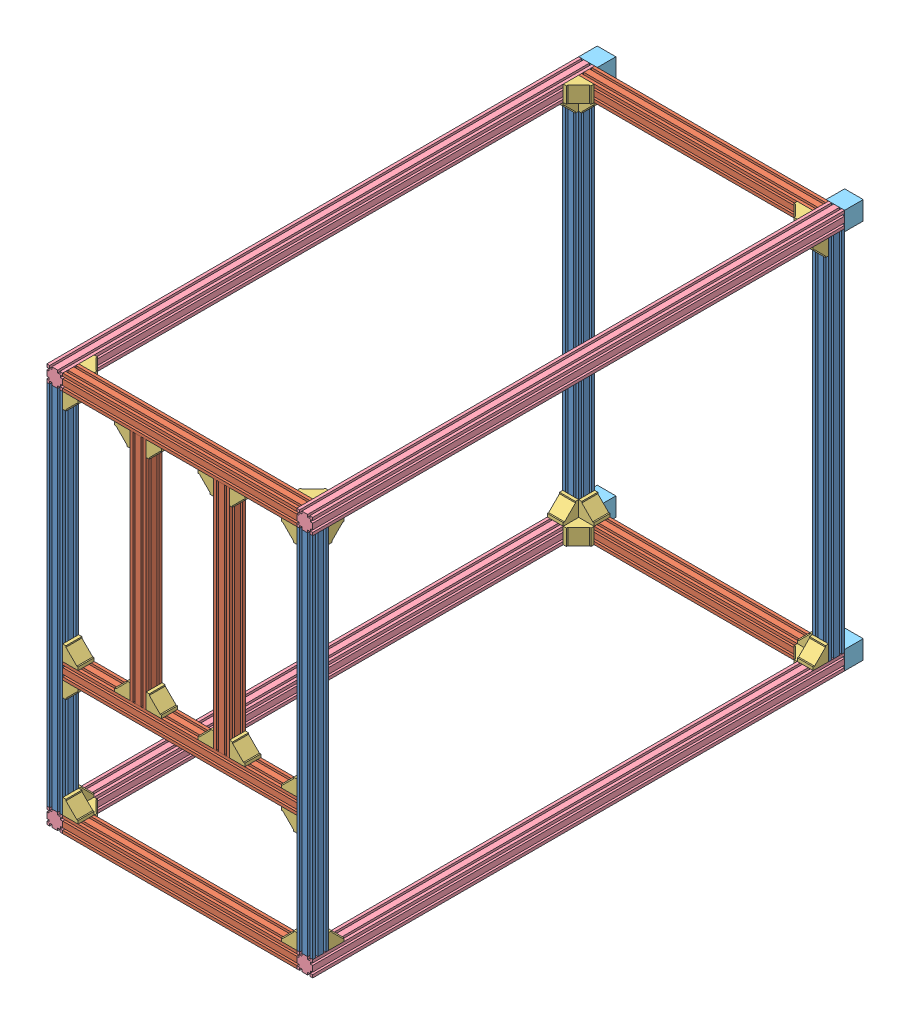
SolidWorks assembly 框架, configuration 默认. Lengths in mm.
Overall size (1000 1500 2070).
55 component instances, 5 part files, 161 mates.
Components (placement in the parent):
- 框架（水平 大）-1: 框架（水平 大） [默认] at (-98.7964 -668.0959 30) size (60 1380 60)
- 框架（水平 大）-2: 框架（水平 大） [默认] at (841.2036 -668.0959 30) size (60 1380 60)
- 框架（水平 小）-1: 框架（水平 小） [默认] at (841.2036 711.9041 30) x (0 1 0) z (0 0 1) size (60 880 60)
- 框架（水平 小）-2: 框架（水平 小） [默认] at (841.2036 -228.0959 30) x (0 1 0) z (0 0 1) size (60 880 60)
- 框架（水平 小）-6: 框架（水平 小） [默认] at (841.2036 -728.0959 30) x (0 1 0) z (0 0 1) size (60 880 60)
- 外角件-1: 外角件 [默认] at (-38.7964 -668.0959 -30) size (58 58 60)
- 外角件-2: 外角件 [默认] at (841.2036 -668.0959 -30) x (0 1 0) z (0 0 1) size (58 58 60)
- 外角件-3: 外角件 [默认] at (841.2036 -228.0959 -30) x (-1 0 0) z (0 0 1) size (58 58 60)
- 外角件-4: 外角件 [默认] at (-38.7964 -228.0959 30) x (1 0 0) z (0 0 -1) size (58 58 60)
- 外角件-5: 外角件 [默认] at (-38.7964 -168.0959 -30) size (58 58 60)
- 外角件-6: 外角件 [默认] at (527.8703 -168.0959 -30) x (0 1 0) z (0 0 1) size (58 58 60)
- 外角件-7: 外角件 [默认] at (-38.7964 711.9041 -30) x (0 -1 0) z (0 0 1) size (58 58 60)
- 外角件-8: 外角件 [默认] at (527.8703 711.9041 30) x (0 -1 0) z (0 0 -1) size (58 58 60)
- 外角件-9: 外角件 [默认] at (587.8703 -168.0959 -30) size (58 58 60)
- 外角件-10: 外角件 [默认] at (841.2036 -168.0959 -30) x (0 1 0) z (0 0 1) size (58 58 60)
- 外角件-11: 外角件 [默认] at (587.8703 711.9041 -30) x (0 -1 0) z (0 0 1) size (58 58 60)
- 外角件-12: 外角件 [默认] at (841.2036 711.9041 -30) x (-1 0 0) z (0 0 1) size (58 58 60)
- 框架（竖直）-1: 框架（竖直） [默认] at (-38.7964 771.9041 30) x (0 -1 0) z (1 0 0) size (60 2000 60)
- 框架（竖直）-2: 框架（竖直） [默认] at (901.2036 711.9041 30) x (-1 0 0) z (0 -1 0) size (60 2000 60)
- 框架（竖直）-3: 框架（竖直） [默认] at (-98.7964 -728.0959 -1970) x (1 0 0) z (0 -1 0) size (60 2000 60)
- 框架（竖直）-4: 框架（竖直） [默认] at (841.2036 -668.0959 30) x (1 0 0) z (0 1 0) size (60 2000 60)
- 框架（水平 小）-7: 框架（水平 小） [默认] at (841.2036 711.9041 -1970) x (0 0 1) z (0 -1 0) size (60 880 60)
- 框架（水平 小）-8: 框架（水平 小） [默认] at (-38.7964 -668.0959 -1910) x (0 -1 0) z (0 0 1) size (60 880 60)
- 框架（水平 大）-3: 框架（水平 大） [默认] at (901.2036 -668.0959 -1910) x (0 0 -1) z (1 0 0) size (60 1380 60)
- 框架（水平 大）-4: 框架（水平 大） [默认] at (-98.7964 -668.0959 -1910) size (60 1380 60)
- 外角件-13: 外角件 [默认] at (-38.7964 -668.0959 -1970) size (58 58 60)
- 外角件-14: 外角件 [默认] at (841.2036 711.9041 -1970) x (-1 0 0) z (0 0 1) size (58 58 60)
- 外角件-15: 外角件 [默认] at (841.2036 -668.0959 -1970) x (0 1 0) z (0 0 1) size (58 58 60)
- 外角件-16: 外角件 [默认] at (-38.7964 711.9041 -1910) x (1 0 0) z (0 0 -1) size (58 58 60)
- 外角件-17: 外角件 [默认] at (-98.7964 711.9041 -30) x (0 -1 0) z (1 0 0) size (58 58 60)
- 外角件-18: 外角件 [默认] at (841.2036 -668.0959 -30) x (0 0 -1) z (1 0 0) size (58 58 60)
- 外角件-19: 外角件 [默认] at (-38.7964 711.9041 -1910) x (0 -1 0) z (-1 0 0) size (58 58 60)
- 外角件-20: 外角件 [默认] at (901.2036 -668.0959 -1910) x (0 0 1) z (-1 0 0) size (58 58 60)
- 外角件-21: 外角件 [默认] at (841.2036 711.9041 -30) x (0 -1 0) z (1 0 0) size (58 58 60)
- 外角件-22: 外角件 [默认] at (841.2036 771.9041 -1910) x (0 0 1) z (0 -1 0) size (58 58 60)
- 外角件-23: 外角件 [默认] at (-98.7964 -668.0959 -30) x (0 0 -1) z (1 0 0) size (58 58 60)
- 外角件-24: 外角件 [默认] at (-38.7964 -668.0959 -1910) x (0 0 1) z (-1 0 0) size (58 58 60)
- 外角件-25: 外角件 [默认] at (841.2036 -668.0959 -1910) x (0 0 1) z (0 -1 0) size (58 58 60)
- 外角件-26: 外角件 [默认] at (-38.7964 -728.0959 -30) x (1 0 0) z (0 1 0) size (58 58 60)
- 外角件-27: 外角件 [默认] at (841.2036 -728.0959 -30) x (0 0 -1) z (0 1 0) size (58 58 60)
- 外角件-28: 外角件 [默认] at (-38.7964 711.9041 -30) x (1 0 0) z (0 1 0) size (58 58 60)
- 外角件-29: 外角件 [默认] at (-38.7964 -668.0959 -1910) x (1 0 0) z (0 -1 0) size (58 58 60)
- 外角件-30: 外角件 [默认] at (841.2036 711.9041 -1910) x (0 0 1) z (1 0 0) size (58 58 60)
- 外角件-31: 外角件 [默认] at (-38.7964 711.9041 -1910) x (0 0 1) z (0 1 0) size (58 58 60)
- 外角件-32: 外角件 [默认] at (841.2036 711.9041 -30) x (0 0 -1) z (0 1 0) size (58 58 60)
- 框架（水平 小）-9: 框架（水平 小） [默认] at (527.8703 -168.0959 30) size (60 880 60)
- 框架（水平 小）-10: 框架（水平 小） [默认] at (214.537 -168.0959 30) size (60 880 60)
- 外角件-33: 外角件 [默认] at (274.537 711.9041 -30) x (0 -1 0) z (0 0 1) size (58 58 60)
- 外角件-34: 外角件 [默认] at (214.537 711.9041 -30) x (-1 0 0) z (0 0 1) size (58 58 60)
- 外角件-35: 外角件 [默认] at (274.537 -168.0959 -30) size (58 58 60)
- 外角件-36: 外角件 [默认] at (214.537 -168.0959 -30) x (0 1 0) z (0 0 1) size (58 58 60)
- 支脚-1: 支脚 [默认] at (831.2036 -728.0959 -1970) size (70 70 70)
- 支脚-2: 支脚 [默认] at (-98.7964 -728.0959 -1970) size (70 70 70)
- 支脚-3: 支脚 [默认] at (-98.7964 701.9041 -1970) size (70 70 70)
- 支脚-4: 支脚 [默认] at (831.2036 701.9041 -1970) size (70 70 70)
Mates (geometry in assembly coordinates):
- 重合21: coincident anti-aligned: plane of 框架（水平 大）-1 through (-38.7964 711.9041 30) normal (1 0 0); plane of 框架（水平 小）-2 through (-38.7964 -228.0959 30) normal (-1 0 0)
- 重合22: coincident anti-aligned: plane of 框架（水平 大）-1 through (-38.7964 711.9041 30) normal (1 0 0); plane of 框架（水平 小）-1 through (-38.7964 711.9041 30) normal (-1 0 0)
- 重合23: coincident aligned: plane of 框架（水平 大）-1 through (-98.7964 711.9041 30) normal (0 0 1); plane of 框架（水平 小）-1 through (-38.7964 711.9041 30) normal (0 0 1)
- 重合24: coincident aligned: plane of 框架（水平 大）-1 through (-98.7964 711.9041 30) normal (0 0 1); plane of 框架（水平 小）-2 through (-38.7964 -228.0959 30) normal (0 0 1)
- 重合29: coincident anti-aligned: plane of 框架（水平 大）-2 through (841.2036 -668.0959 30) normal (0 -1 0); plane of 框架（水平 小）-6 through (-38.7964 -668.0959 30) normal (0 1 0)
- 重合30: coincident aligned: plane of 框架（水平 大）-2 through (841.2036 711.9041 30) normal (0 0 1); plane of 框架（水平 小）-6 through (-38.7964 -728.0959 30) normal (0 0 1)
- 重合35: coincident anti-aligned: plane of 框架（水平 大）-2 through (841.2036 711.9041 30) normal (-1 0 0); plane of 框架（水平 小）-6 through (841.2036 -728.0959 30) normal (1 0 0)
- 重合37: coincident anti-aligned: plane of 框架（水平 大）-1 through (-98.7964 711.9041 30) normal (0 1 0); plane of 框架（水平 小）-1 through (-38.7964 711.9041 30) normal (0 -1 0)
- 重合40: coincident anti-aligned: plane of 框架（水平 大）-2 through (841.2036 711.9041 30) normal (-1 0 0); plane of 框架（水平 小）-2 through (841.2036 -228.0959 30) normal (1 0 0)
- 重合41: coincident aligned: plane of 框架（水平 大）-2 through (841.2036 711.9041 30) normal (0 0 1); plane of 框架（水平 小）-2 through (-38.7964 -228.0959 30) normal (0 0 1)
- 重合42: coincident anti-aligned: plane of 框架（水平 大）-1 through (-98.7964 -668.0959 30) normal (0 -1 0); plane of 框架（水平 小）-6 through (-38.7964 -668.0959 30) normal (0 1 0)
- 重合43: coincident anti-aligned: plane of 框架（水平 大）-1 through (-38.7964 711.9041 30) normal (1 0 0); plane of 外角件-1 through (-38.7964 -610.0959 30) normal (-1 0 0)
- 重合44: coincident anti-aligned: plane of 框架（水平 小）-6 through (-38.7964 -668.0959 30) normal (0 1 0); plane of 外角件-1 through (-38.7964 -668.0959 30) normal (0 -1 0)
- 重合45: coincident aligned: plane of 框架（水平 大）-1 through (-98.7964 711.9041 30) normal (0 0 1); plane of 外角件-1 through (-38.7964 -668.0959 30) normal (0 0 1)
- 重合46: coincident anti-aligned: plane of 框架（水平 小）-2 through (-38.7964 -228.0959 30) normal (0 -1 0); plane of 外角件-4 through (-38.7964 -228.0959 -30) normal (0 1 0)
- 重合47: coincident anti-aligned: plane of 框架（水平 大）-1 through (-38.7964 711.9041 30) normal (1 0 0); plane of 外角件-4 through (-38.7964 -286.0959 -30) normal (-1 0 0)
- 重合48: coincident aligned: plane of 框架（水平 大）-1 through (-98.7964 711.9041 30) normal (0 0 1); plane of 外角件-4 through (-38.7964 -228.0959 30) normal (0 0 1)
- 重合49: coincident anti-aligned: plane of 框架（水平 小）-2 through (-38.7964 -168.0959 30) normal (0 1 0); plane of 外角件-5 through (-38.7964 -168.0959 30) normal (0 -1 0)
- 重合50: coincident anti-aligned: plane of 框架（水平 大）-1 through (-38.7964 711.9041 30) normal (1 0 0); plane of 外角件-5 through (-38.7964 -110.0959 30) normal (-1 0 0)
- 重合51: coincident aligned: plane of 框架（水平 大）-1 through (-98.7964 711.9041 30) normal (0 0 1); plane of 外角件-5 through (-38.7964 -168.0959 30) normal (0 0 1)
- 重合52: coincident anti-aligned: plane of 框架（水平 小）-1 through (-38.7964 711.9041 30) normal (0 -1 0); plane of 外角件-7 through (19.2036 711.9041 30) normal (0 1 0)
- 重合53: coincident anti-aligned: plane of 框架（水平 大）-1 through (-38.7964 711.9041 30) normal (1 0 0); plane of 外角件-7 through (-38.7964 711.9041 30) normal (-1 0 0)
- 重合54: coincident aligned: plane of 框架（水平 大）-1 through (-98.7964 711.9041 30) normal (0 0 1); plane of 外角件-7 through (-38.7964 711.9041 30) normal (0 0 1)
- 重合55: coincident anti-aligned: plane of 框架（水平 小）-1 through (-38.7964 711.9041 30) normal (0 -1 0); plane of 外角件-8 through (469.8703 711.9041 -30) normal (0 1 0)
- 重合58: coincident anti-aligned: plane of 框架（水平 小）-2 through (-38.7964 -168.0959 30) normal (0 1 0); plane of 外角件-6 through (469.8703 -168.0959 30) normal (0 -1 0)
- 重合60: coincident aligned: plane of 框架（水平 小）-2 through (-38.7964 -228.0959 30) normal (0 0 1); plane of 外角件-6 through (527.8703 -168.0959 30) normal (0 0 1)
- 重合62: coincident anti-aligned: plane of 框架（水平 小）-2 through (-38.7964 -168.0959 30) normal (0 1 0); plane of 外角件-9 through (587.8703 -168.0959 30) normal (0 -1 0)
- 重合64: coincident anti-aligned: plane of 框架（水平 小）-2 through (-38.7964 -168.0959 30) normal (0 1 0); plane of 外角件-10 through (783.2036 -168.0959 30) normal (0 -1 0)
- 重合65: coincident anti-aligned: plane of 框架（水平 大）-2 through (841.2036 711.9041 30) normal (-1 0 0); plane of 外角件-10 through (841.2036 -168.0959 30) normal (1 0 0)
- 重合66: coincident aligned: plane of 框架（水平 小）-2 through (-38.7964 -228.0959 30) normal (0 0 1); plane of 外角件-10 through (841.2036 -168.0959 30) normal (0 0 1)
- 重合68: coincident anti-aligned: plane of 框架（水平 小）-2 through (-38.7964 -228.0959 30) normal (0 -1 0); plane of 外角件-3 through (841.2036 -228.0959 30) normal (0 1 0)
- 重合69: coincident anti-aligned: plane of 框架（水平 大）-2 through (841.2036 711.9041 30) normal (-1 0 0); plane of 外角件-3 through (841.2036 -286.0959 30) normal (1 0 0)
- 重合70: coincident aligned: plane of 框架（水平 小）-2 through (-38.7964 -228.0959 30) normal (0 0 1); plane of 外角件-3 through (841.2036 -228.0959 30) normal (0 0 1)
- 重合71: coincident anti-aligned: plane of 框架（水平 大）-2 through (841.2036 711.9041 30) normal (-1 0 0); plane of 外角件-2 through (841.2036 -668.0959 30) normal (1 0 0)
- 重合72: coincident anti-aligned: plane of 框架（水平 小）-6 through (-38.7964 -668.0959 30) normal (0 1 0); plane of 外角件-2 through (783.2036 -668.0959 30) normal (0 -1 0)
- 重合73: coincident aligned: plane of 框架（水平 大）-2 through (841.2036 711.9041 30) normal (0 0 1); plane of 外角件-2 through (841.2036 -668.0959 30) normal (0 0 1)
- 重合75: coincident anti-aligned: plane of 框架（水平 小）-1 through (-38.7964 711.9041 30) normal (0 -1 0); plane of 外角件-11 through (645.8703 711.9041 30) normal (0 1 0)
- 重合77: coincident anti-aligned: plane of 框架（水平 大）-2 through (841.2036 711.9041 30) normal (-1 0 0); plane of 外角件-12 through (841.2036 653.9041 30) normal (1 0 0)
- 重合78: coincident anti-aligned: plane of 框架（水平 小）-1 through (-38.7964 711.9041 30) normal (0 -1 0); plane of 外角件-12 through (841.2036 711.9041 30) normal (0 1 0)
- 重合79: coincident aligned: plane of 框架（水平 大）-2 through (841.2036 711.9041 30) normal (0 0 1); plane of 外角件-12 through (841.2036 711.9041 30) normal (0 0 1)
- 重合80: coincident aligned: plane of 框架（水平 大）-1 through (-98.7964 711.9041 30) normal (0 0 1); plane of 框架（竖直）-1 through (-38.7964 771.9041 30) normal (0 0 1)
- 重合81: coincident anti-aligned: plane of 框架（水平 大）-1 through (-98.7964 711.9041 30) normal (0 1 0); plane of 框架（竖直）-1 through (-38.7964 711.9041 -1970) normal (0 -1 0)
- 重合82: coincident anti-aligned: plane of 框架（水平 小）-1 through (-38.7964 711.9041 30) normal (-1 0 0); plane of 框架（竖直）-1 through (-38.7964 771.9041 -1970) normal (1 0 0)
- 重合83: coincident aligned: plane of 框架（竖直）-1 through (-38.7964 771.9041 30) normal (0 0 1); plane of 框架（竖直）-2 through (901.2036 711.9041 30) normal (0 0 1)
- 重合84: coincident anti-aligned: plane of 框架（水平 大）-2 through (841.2036 711.9041 30) normal (0 1 0); plane of 框架（竖直）-2 through (901.2036 711.9041 -1970) normal (0 -1 0)
- 重合85: coincident: line of 框架（水平 小）-1 through (841.2036 771.9041 -19.1) axis (0 0 -1); plane of 框架（竖直）-2 through (841.2036 711.9041 -1970) normal (-1 0 0)
- 重合86: coincident aligned: plane of 框架（竖直）-1 through (-38.7964 771.9041 30) normal (0 0 1); plane of 框架（竖直）-3 through (-98.7964 -728.0959 30) normal (0 0 1)
- 重合87: coincident anti-aligned: plane of 框架（水平 小）-6 through (-38.7964 -728.0959 30) normal (-1 0 0); plane of 框架（竖直）-3 through (-38.7964 -728.0959 30) normal (1 0 0)
- 重合88: coincident anti-aligned: plane of 框架（水平 大）-1 through (-98.7964 -668.0959 30) normal (0 -1 0); plane of 框架（竖直）-3 through (-98.7964 -668.0959 30) normal (0 1 0)
- 重合89: coincident aligned: plane of 框架（竖直）-3 through (-98.7964 -728.0959 30) normal (0 0 1); plane of 框架（竖直）-4 through (841.2036 -668.0959 30) normal (0 0 1)
- 重合90: coincident anti-aligned: plane of 框架（水平 大）-2 through (841.2036 -668.0959 30) normal (0 -1 0); plane of 框架（竖直）-4 through (841.2036 -668.0959 -1970) normal (0 1 0)
- 重合91: coincident anti-aligned: plane of 框架（水平 小）-6 through (841.2036 -728.0959 30) normal (1 0 0); plane of 框架（竖直）-4 through (841.2036 -668.0959 -1970) normal (-1 0 0)
- 重合92: coincident aligned: plane of 框架（竖直）-1 through (-98.7964 771.9041 -1970) normal (-1 0 0); plane of 框架（水平 大）-4 through (-98.7964 711.9041 -1910) normal (-1 0 0)
- 重合93: coincident anti-aligned: plane of 框架（竖直）-3 through (-98.7964 -668.0959 30) normal (0 1 0); plane of 框架（水平 大）-4 through (-98.7964 -668.0959 -1910) normal (0 -1 0)
- 重合94: coincident aligned: plane of 框架（竖直）-1 through (-38.7964 771.9041 -1970) normal (0 0 -1); plane of 框架（水平 大）-4 through (-98.7964 711.9041 -1970) normal (0 0 -1)
- 重合95: coincident aligned: plane of 框架（竖直）-2 through (901.2036 711.9041 -1970) normal (0 0 -1); plane of 框架（水平 小）-7 through (-38.7964 711.9041 -1970) normal (0 0 -1)
- 重合96: coincident anti-aligned: plane of 框架（竖直）-1 through (-38.7964 771.9041 -1970) normal (1 0 0); plane of 框架（水平 小）-7 through (-38.7964 711.9041 -1970) normal (-1 0 0)
- 重合97: coincident aligned: plane of 框架（竖直）-1 through (-38.7964 771.9041 -1970) normal (0 1 0); plane of 框架（水平 小）-7 through (-38.7964 771.9041 -1970) normal (0 1 0)
- 重合98: coincident aligned: plane of 框架（竖直）-4 through (841.2036 -668.0959 -1970) normal (0 0 -1); plane of 框架（水平 大）-3 through (901.2036 711.9041 -1970) normal (0 0 -1)
- 重合99: coincident anti-aligned: plane of 框架（竖直）-4 through (841.2036 -668.0959 -1970) normal (0 1 0); plane of 框架（水平 大）-3 through (901.2036 -668.0959 -1910) normal (0 -1 0)
- 重合100: coincident aligned: plane of 框架（竖直）-4 through (901.2036 -668.0959 -1970) normal (1 0 0); plane of 框架（水平 大）-3 through (901.2036 711.9041 -1910) normal (1 0 0)
- 重合101: coincident anti-aligned: plane of 框架（竖直）-3 through (-38.7964 -728.0959 30) normal (1 0 0); plane of 框架（水平 小）-8 through (-38.7964 -668.0959 -1910) normal (-1 0 0)
- 重合102: coincident aligned: plane of 框架（竖直）-3 through (-98.7964 -728.0959 30) normal (0 -1 0); plane of 框架（水平 小）-8 through (841.2036 -728.0959 -1910) normal (0 -1 0)
- 重合103: coincident aligned: plane of 框架（竖直）-3 through (-98.7964 -728.0959 -1970) normal (0 0 -1); plane of 框架（水平 小）-8 through (841.2036 -668.0959 -1970) normal (0 0 -1)
- 重合104: coincident aligned: plane of 框架（竖直）-2 through (901.2036 711.9041 -1970) normal (0 0 -1); plane of 外角件-14 through (841.2036 711.9041 -1970) normal (0 0 -1)
- 重合105: coincident anti-aligned: plane of 框架（水平 大）-3 through (841.2036 711.9041 -1910) normal (-1 0 0); plane of 外角件-14 through (841.2036 653.9041 -1910) normal (1 0 0)
- 重合107: coincident anti-aligned: plane of 框架（水平 小）-7 through (-38.7964 711.9041 -1970) normal (0 -1 0); plane of 外角件-14 through (841.2036 711.9041 -1910) normal (0 1 0)
- 重合108: coincident aligned: plane of 框架（水平 大）-4 through (-98.7964 711.9041 -1910) normal (0 0 1); plane of 外角件-13 through (-38.7964 -668.0959 -1910) normal (0 0 1)
- 重合109: coincident anti-aligned: plane of 框架（水平 小）-8 through (841.2036 -668.0959 -1910) normal (0 1 0); plane of 外角件-13 through (-38.7964 -668.0959 -1910) normal (0 -1 0)
- 重合110: coincident aligned: line of 框架（水平 大）-4 through (-38.7964 711.9041 -1910) axis (0 -1 0); line of 外角件-13 through (-38.7964 -610.0959 -1910) axis (0 -1 0)
- 重合111: coincident anti-aligned: plane of 框架（水平 大）-4 through (-38.7964 711.9041 -1910) normal (1 0 0); plane of 外角件-16 through (-38.7964 653.9041 -1970) normal (-1 0 0)
- 重合112: coincident anti-aligned: plane of 框架（水平 小）-7 through (-38.7964 711.9041 -1970) normal (0 -1 0); plane of 外角件-16 through (-38.7964 711.9041 -1970) normal (0 1 0)
- 重合113: coincident aligned: plane of 框架（水平 大）-4 through (-98.7964 711.9041 -1910) normal (0 0 1); plane of 外角件-16 through (-38.7964 711.9041 -1910) normal (0 0 1)
- 重合114: coincident anti-aligned: plane of 框架（水平 小）-8 through (841.2036 -668.0959 -1910) normal (0 1 0); plane of 外角件-15 through (783.2036 -668.0959 -1910) normal (0 -1 0)
- 重合115: coincident anti-aligned: plane of 框架（水平 大）-3 through (841.2036 711.9041 -1910) normal (-1 0 0); plane of 外角件-15 through (841.2036 -668.0959 -1910) normal (1 0 0)
- 重合116: coincident aligned: plane of 框架（水平 小）-8 through (841.2036 -668.0959 -1910) normal (0 0 1); plane of 外角件-15 through (841.2036 -668.0959 -1910) normal (0 0 1)
- 重合117: coincident anti-aligned: plane of 框架（竖直）-1 through (-38.7964 711.9041 -1970) normal (0 -1 0); plane of 外角件-17 through (-38.7964 711.9041 -88) normal (0 1 0)
- 重合118: coincident anti-aligned: plane of 框架（水平 大）-1 through (-98.7964 711.9041 -30) normal (0 0 -1); plane of 外角件-17 through (-38.7964 711.9041 -30) normal (0 0 1)
- 重合119: coincident aligned: plane of 框架（竖直）-1 through (-98.7964 771.9041 -1970) normal (-1 0 0); plane of 外角件-17 through (-98.7964 711.9041 -30) normal (-1 0 0)
- 重合120: coincident anti-aligned: plane of 框架（水平 大）-2 through (841.2036 711.9041 -30) normal (0 0 -1); plane of 外角件-21 through (901.2036 711.9041 -30) normal (0 0 1)
- 重合121: coincident anti-aligned: plane of 框架（竖直）-2 through (901.2036 711.9041 -1970) normal (0 -1 0); plane of 外角件-21 through (901.2036 711.9041 -88) normal (0 1 0)
- 重合122: coincident aligned: plane of 框架（竖直）-2 through (841.2036 711.9041 -1970) normal (-1 0 0); plane of 外角件-21 through (841.2036 711.9041 -30) normal (-1 0 0)
- 重合123: coincident anti-aligned: plane of 框架（水平 大）-2 through (841.2036 711.9041 -30) normal (0 0 -1); plane of 外角件-18 through (901.2036 -610.0959 -30) normal (0 0 1)
- 重合124: coincident anti-aligned: plane of 框架（竖直）-4 through (841.2036 -668.0959 -1970) normal (0 1 0); plane of 外角件-18 through (901.2036 -668.0959 -30) normal (0 -1 0)
- 重合125: coincident aligned: plane of 框架（水平 大）-2 through (841.2036 711.9041 30) normal (-1 0 0); plane of 外角件-18 through (841.2036 -668.0959 -30) normal (-1 0 0)
- 重合126: coincident anti-aligned: plane of 框架（水平 大）-1 through (-98.7964 711.9041 -30) normal (0 0 -1); plane of 外角件-23 through (-38.7964 -610.0959 -30) normal (0 0 1)
- 重合127: coincident anti-aligned: plane of 框架（竖直）-3 through (-98.7964 -668.0959 30) normal (0 1 0); plane of 外角件-23 through (-38.7964 -668.0959 -30) normal (0 -1 0)
- 重合128: coincident aligned: plane of 框架（水平 大）-1 through (-98.7964 711.9041 30) normal (-1 0 0); plane of 外角件-23 through (-98.7964 -668.0959 -30) normal (-1 0 0)
- 重合129: coincident anti-aligned: plane of 框架（水平 大）-4 through (-98.7964 711.9041 -1910) normal (0 0 1); plane of 外角件-24 through (-98.7964 -610.0959 -1910) normal (0 0 -1)
- 重合130: coincident anti-aligned: plane of 框架（竖直）-3 through (-98.7964 -668.0959 30) normal (0 1 0); plane of 外角件-24 through (-98.7964 -668.0959 -1910) normal (0 -1 0)
- 重合131: coincident aligned: plane of 框架（竖直）-3 through (-98.7964 -728.0959 30) normal (-1 0 0); plane of 外角件-24 through (-98.7964 -668.0959 -1910) normal (-1 0 0)
- 重合132: coincident anti-aligned: plane of 框架（竖直）-1 through (-38.7964 711.9041 -1970) normal (0 -1 0); plane of 外角件-19 through (-98.7964 711.9041 -1852) normal (0 1 0)
- 重合133: coincident anti-aligned: plane of 框架（水平 大）-4 through (-98.7964 711.9041 -1910) normal (0 0 1); plane of 外角件-19 through (-98.7964 711.9041 -1910) normal (0 0 -1)
- 重合134: coincident aligned: plane of 框架（竖直）-1 through (-98.7964 771.9041 -1970) normal (-1 0 0); plane of 外角件-19 through (-98.7964 711.9041 -1910) normal (-1 0 0)
- 重合135: coincident anti-aligned: plane of 框架（水平 小）-7 through (-38.7964 711.9041 -1910) normal (0 0 1); plane of 外角件-22 through (783.2036 711.9041 -1910) normal (0 0 -1)
- 重合136: coincident anti-aligned: plane of 框架（竖直）-2 through (841.2036 711.9041 -1970) normal (-1 0 0); plane of 外角件-22 through (841.2036 711.9041 -1910) normal (1 0 0)
- 重合137: coincident aligned: plane of 框架（竖直）-2 through (901.2036 771.9041 -1970) normal (0 1 0); plane of 外角件-22 through (841.2036 771.9041 -1910) normal (0 1 0)
- 重合138: coincident anti-aligned: plane of 框架（竖直）-4 through (841.2036 -668.0959 -1970) normal (0 1 0); plane of 外角件-20 through (841.2036 -668.0959 -1910) normal (0 -1 0)
- 重合139: coincident anti-aligned: plane of 框架（水平 大）-3 through (901.2036 711.9041 -1910) normal (0 0 1); plane of 外角件-20 through (841.2036 -610.0959 -1910) normal (0 0 -1)
- 重合140: coincident aligned: plane of 框架（竖直）-4 through (901.2036 -668.0959 -1970) normal (1 0 0); plane of 外角件-20 through (901.2036 -668.0959 -1910) normal (1 0 0)
- 重合141: coincident anti-aligned: plane of 框架（水平 小）-8 through (841.2036 -668.0959 -1910) normal (0 0 1); plane of 外角件-29 through (-38.7964 -728.0959 -1910) normal (0 0 -1)
- 重合142: coincident anti-aligned: plane of 框架（竖直）-3 through (-38.7964 -728.0959 30) normal (1 0 0); plane of 外角件-29 through (-38.7964 -728.0959 -1852) normal (-1 0 0)
- 重合143: coincident aligned: plane of 框架（竖直）-3 through (-98.7964 -728.0959 30) normal (0 -1 0); plane of 外角件-29 through (-38.7964 -728.0959 -1910) normal (0 -1 0)
- 重合144: coincident anti-aligned: plane of 框架（竖直）-4 through (841.2036 -668.0959 -1970) normal (-1 0 0); plane of 外角件-25 through (841.2036 -728.0959 -1910) normal (1 0 0)
- 重合145: coincident anti-aligned: plane of 框架（水平 小）-8 through (841.2036 -668.0959 -1910) normal (0 0 1); plane of 外角件-25 through (783.2036 -728.0959 -1910) normal (0 0 -1)
- 重合146: coincident aligned: plane of 框架（竖直）-4 through (841.2036 -728.0959 -1970) normal (0 -1 0); plane of 外角件-25 through (841.2036 -728.0959 -1910) normal (0 -1 0)
- 重合147: coincident anti-aligned: plane of 框架（竖直）-4 through (841.2036 -668.0959 -1970) normal (-1 0 0); plane of 外角件-27 through (841.2036 -668.0959 -30) normal (1 0 0)
- 重合148: coincident anti-aligned: plane of 框架（水平 小）-6 through (-38.7964 -728.0959 -30) normal (0 0 -1); plane of 外角件-27 through (783.2036 -668.0959 -30) normal (0 0 1)
- 重合149: coincident aligned: plane of 框架（竖直）-4 through (841.2036 -728.0959 -1970) normal (0 -1 0); plane of 外角件-27 through (841.2036 -728.0959 -30) normal (0 -1 0)
- 重合150: coincident anti-aligned: plane of 框架（水平 小）-6 through (-38.7964 -728.0959 -30) normal (0 0 -1); plane of 外角件-26 through (-38.7964 -668.0959 -30) normal (0 0 1)
- 重合151: coincident anti-aligned: plane of 框架（竖直）-3 through (-38.7964 -728.0959 30) normal (1 0 0); plane of 外角件-26 through (-38.7964 -668.0959 -88) normal (-1 0 0)
- 重合152: coincident aligned: plane of 框架（水平 小）-6 through (-38.7964 -728.0959 30) normal (0 -1 0); plane of 外角件-26 through (-38.7964 -728.0959 -30) normal (0 -1 0)
- 重合153: coincident anti-aligned: plane of 框架（水平 小）-1 through (-38.7964 711.9041 -30) normal (0 0 -1); plane of 外角件-28 through (-38.7964 771.9041 -30) normal (0 0 1)
- 重合154: coincident anti-aligned: plane of 框架（竖直）-1 through (-38.7964 771.9041 -1970) normal (1 0 0); plane of 外角件-28 through (-38.7964 771.9041 -88) normal (-1 0 0)
- 重合155: coincident aligned: plane of 框架（竖直）-1 through (-38.7964 771.9041 -1970) normal (0 1 0); plane of 外角件-28 through (-38.7964 771.9041 -30) normal (0 1 0)
- 重合159: coincident anti-aligned: plane of 框架（水平 大）-3 through (901.2036 711.9041 -1910) normal (0 0 1); plane of 外角件-30 through (901.2036 653.9041 -1910) normal (0 0 -1)
- 重合160: coincident anti-aligned: plane of 框架（竖直）-2 through (901.2036 711.9041 -1970) normal (0 -1 0); plane of 外角件-30 through (901.2036 711.9041 -1910) normal (0 1 0)
- 重合161: coincident aligned: plane of 框架（竖直）-2 through (901.2036 711.9041 -1970) normal (1 0 0); plane of 外角件-30 through (901.2036 711.9041 -1910) normal (1 0 0)
- 重合162: coincident anti-aligned: plane of 框架（竖直）-1 through (-38.7964 771.9041 -1970) normal (1 0 0); plane of 外角件-31 through (-38.7964 771.9041 -1910) normal (-1 0 0)
- 重合163: coincident anti-aligned: plane of 框架（水平 小）-7 through (-38.7964 711.9041 -1910) normal (0 0 1); plane of 外角件-31 through (19.2036 771.9041 -1910) normal (0 0 -1)
- 重合164: coincident aligned: plane of 框架（竖直）-1 through (-38.7964 771.9041 -1970) normal (0 1 0); plane of 外角件-31 through (-38.7964 771.9041 -1910) normal (0 1 0)
- 重合165: coincident anti-aligned: plane of 框架（竖直）-2 through (841.2036 711.9041 -1970) normal (-1 0 0); plane of 外角件-32 through (841.2036 771.9041 -30) normal (1 0 0)
- 重合166: coincident anti-aligned: plane of 框架（水平 小）-1 through (-38.7964 711.9041 -30) normal (0 0 -1); plane of 外角件-32 through (783.2036 771.9041 -30) normal (0 0 1)
- 重合167: coincident aligned: plane of 框架（竖直）-2 through (901.2036 771.9041 -1970) normal (0 1 0); plane of 外角件-32 through (841.2036 771.9041 -30) normal (0 1 0)
- 距离1: distance = 253.3333 mm anti-aligned: plane of 框架（水平 大）-2 through (841.2036 711.9041 30) normal (-1 0 0); plane of 框架（水平 小）-9 through (587.8703 711.9041 30) normal (1 0 0)
- 距离2: distance = 253.3333 mm anti-aligned: plane of 框架（水平 小）-10 through (214.537 711.9041 30) normal (-1 0 0); plane of 框架（水平 大）-1 through (-38.7964 711.9041 30) normal (1 0 0)
- 重合170: coincident aligned: plane of 框架（水平 小）-1 through (-38.7964 711.9041 30) normal (0 0 1); plane of 框架（水平 小）-9 through (527.8703 711.9041 30) normal (0 0 1)
- 重合171: coincident anti-aligned: plane of 框架（水平 小）-2 through (-38.7964 -168.0959 30) normal (0 1 0); plane of 框架（水平 小）-9 through (527.8703 -168.0959 30) normal (0 -1 0)
- 重合172: coincident aligned: plane of 框架（水平 小）-1 through (-38.7964 711.9041 30) normal (0 0 1); plane of 框架（水平 小）-10 through (214.537 711.9041 30) normal (0 0 1)
- 重合173: coincident anti-aligned: plane of 框架（水平 小）-2 through (-38.7964 -168.0959 30) normal (0 1 0); plane of 框架（水平 小）-10 through (214.537 -168.0959 30) normal (0 -1 0)
- 重合174: coincident anti-aligned: plane of 外角件-11 through (587.8703 711.9041 30) normal (-1 0 0); plane of 框架（水平 小）-9 through (587.8703 711.9041 30) normal (1 0 0)
- 重合175: coincident aligned: plane of 框架（水平 小）-1 through (-38.7964 711.9041 30) normal (0 0 1); plane of 外角件-11 through (587.8703 711.9041 30) normal (0 0 1)
- 重合176: coincident aligned: plane of 框架（水平 小）-1 through (-38.7964 711.9041 30) normal (0 0 1); plane of 外角件-8 through (527.8703 711.9041 30) normal (0 0 1)
- 重合177: coincident anti-aligned: plane of 外角件-8 through (527.8703 711.9041 -30) normal (1 0 0); plane of 框架（水平 小）-9 through (527.8703 711.9041 30) normal (-1 0 0)
- 重合178: coincident aligned: plane of 框架（水平 小）-2 through (-38.7964 -228.0959 30) normal (0 0 1); plane of 外角件-9 through (587.8703 -168.0959 30) normal (0 0 1)
- 重合179: coincident anti-aligned: plane of 外角件-9 through (587.8703 -110.0959 30) normal (-1 0 0); plane of 框架（水平 小）-9 through (587.8703 711.9041 30) normal (1 0 0)
- 重合180: coincident anti-aligned: plane of 外角件-6 through (527.8703 -168.0959 30) normal (1 0 0); plane of 框架（水平 小）-9 through (527.8703 711.9041 30) normal (-1 0 0)
- 重合181: coincident anti-aligned: plane of 框架（水平 小）-10 through (274.537 711.9041 30) normal (1 0 0); plane of 外角件-33 through (274.537 711.9041 30) normal (-1 0 0)
- 重合182: coincident anti-aligned: plane of 框架（水平 小）-1 through (-38.7964 711.9041 30) normal (0 -1 0); plane of 外角件-33 through (332.537 711.9041 30) normal (0 1 0)
- 重合183: coincident aligned: plane of 框架（水平 小）-10 through (214.537 711.9041 30) normal (0 0 1); plane of 外角件-33 through (274.537 711.9041 30) normal (0 0 1)
- 重合184: coincident anti-aligned: plane of 框架（水平 小）-1 through (-38.7964 711.9041 30) normal (0 -1 0); plane of 外角件-34 through (214.537 711.9041 30) normal (0 1 0)
- 重合185: coincident anti-aligned: plane of 框架（水平 小）-10 through (214.537 711.9041 30) normal (-1 0 0); plane of 外角件-34 through (214.537 653.9041 30) normal (1 0 0)
- 重合186: coincident aligned: plane of 框架（水平 小）-1 through (-38.7964 711.9041 30) normal (0 0 1); plane of 外角件-34 through (214.537 711.9041 30) normal (0 0 1)
- 重合187: coincident anti-aligned: plane of 框架（水平 小）-2 through (-38.7964 -168.0959 30) normal (0 1 0); plane of 外角件-36 through (156.537 -168.0959 30) normal (0 -1 0)
- 重合188: coincident anti-aligned: plane of 框架（水平 小）-10 through (214.537 711.9041 30) normal (-1 0 0); plane of 外角件-36 through (214.537 -168.0959 30) normal (1 0 0)
- 重合189: coincident aligned: plane of 框架（水平 小）-10 through (214.537 711.9041 30) normal (0 0 1); plane of 外角件-36 through (214.537 -168.0959 30) normal (0 0 1)
- 重合190: coincident anti-aligned: plane of 框架（水平 小）-2 through (-38.7964 -168.0959 30) normal (0 1 0); plane of 外角件-35 through (274.537 -168.0959 30) normal (0 -1 0)
- 重合191: coincident anti-aligned: plane of 框架（水平 小）-10 through (274.537 711.9041 30) normal (1 0 0); plane of 外角件-35 through (274.537 -110.0959 30) normal (-1 0 0)
- 重合192: coincident aligned: plane of 框架（水平 小）-2 through (-38.7964 -228.0959 30) normal (0 0 1); plane of 外角件-35 through (274.537 -168.0959 30) normal (0 0 1)
- 重合193: coincident: plane of 框架（竖直）-4 through (901.2036 -668.0959 -1970) normal (1 0 0); plane of 支脚-1 through (901.2036 -658.0959 -1970) normal (1 0 0)
- 重合194: coincident: plane of 框架（竖直）-4 through (841.2036 -728.0959 -1970) normal (0 -1 0); plane of 支脚-1 through (831.2036 -728.0959 -1970) normal (0 -1 0)
- 重合195: coincident: plane of 框架（水平 小）-8 through (841.2036 -668.0959 -1970) normal (0 0 -1); line of 支脚-1 through (831.2036 -728.0959 -1970) axis (1 0 0)
- 重合196: coincident: plane of 框架（水平 小）-8 through (841.2036 -728.0959 -1910) normal (0 -1 0); plane of 支脚-2 through (-98.7964 -728.0959 -1970) normal (0 -1 0)
- 重合197: coincident: plane of 框架（竖直）-3 through (-98.7964 -728.0959 30) normal (-1 0 0); plane of 支脚-2 through (-98.7964 -658.0959 -1970) normal (-1 0 0)
- 重合198: coincident: plane of 框架（水平 大）-4 through (-98.7964 711.9041 -1970) normal (0 0 -1); line of 支脚-2 through (-98.7964 -728.0959 -1970) axis (1 0 0)
- 重合199: coincident: plane of 框架（竖直）-1 through (-98.7964 771.9041 -1970) normal (-1 0 0); plane of 支脚-3 through (-98.7964 771.9041 -1970) normal (-1 0 0)
- 重合200: coincident: plane of 框架（水平 小）-7 through (-38.7964 771.9041 -1970) normal (0 1 0); line of 支脚-3 through (-98.7964 771.9041 -2040) axis (0 0 1)
- 重合201: coincident aligned: line of 框架（竖直）-1 through (-98.7964 752.8041 -1970) axis (0 -1 0); line of 支脚-3 through (-98.7964 771.9041 -1970) axis (0 -1 0)
- 重合202: coincident: plane of 框架（竖直）-2 through (901.2036 711.9041 -1970) normal (0 0 -1); plane of 支脚-4 through (831.2036 771.9041 -1970) normal (0 0 1)
- 重合203: coincident: plane of 框架（竖直）-2 through (901.2036 771.9041 -1970) normal (0 1 0); plane of 支脚-4 through (831.2036 771.9041 -1970) normal (0 1 0)
- 重合204: coincident aligned: plane of 框架（竖直）-2 through (901.2036 711.9041 -1970) normal (1 0 0); plane of 支脚-4 through (901.2036 771.9041 -1970) normal (1 0 0)
